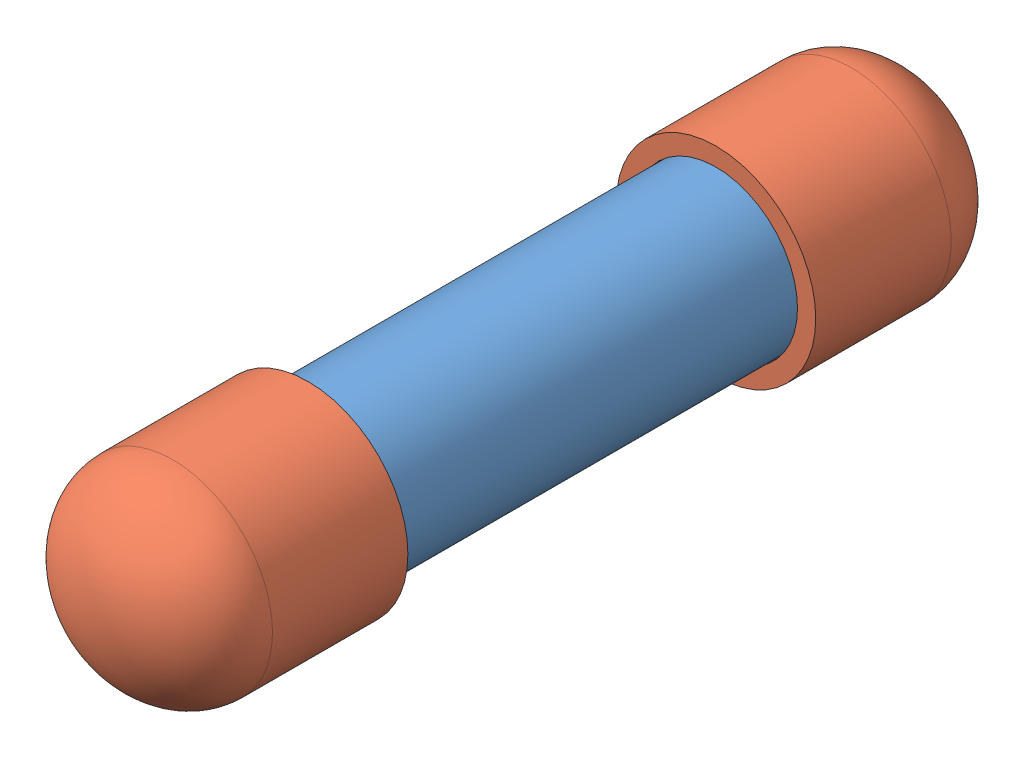
SolidWorks assembly OIL SAMPLE, configuration Default. Lengths in mm.
Overall size (41.17 41.17 172.16).
3 component instances, 2 part files, 4 mates.
Components (placement in the parent):
- 1 PVC PIPE 14CM-1: 1 PVC PIPE 14CM [48925K93] at (55.8359 74.6326 104.5055) size (33.4 33.4 140)
- 1 PVC CAP-1: 1 PVC CAP [4880K53] at (55.8359 74.6326 168.5746) x (0 0 1) z (-1 0 0) size (44.02 41.17 41.17)
- 1 PVC CAP-2: 1 PVC CAP [4880K53] at (55.8359 74.6326 40.4364) x (0 0 -1) z (1 0 0) size (44.02 41.17 41.17)
Mates (geometry in assembly coordinates):
- Coincident1: coincident anti-aligned: plane of 1 PVC PIPE 14CM-1 through (55.8359 74.6326 174.5055) normal (0 0 1); circle of 1 PVC CAP-1
- Concentric1: concentric aligned: cylinder of 1 PVC PIPE 14CM-1 through (55.8359 74.6326 174.5055) axis (0 0 -1) radius 16.7005; cylinder of 1 PVC CAP-1 through (55.8359 74.6326 146.5655) axis (0 0 -1) radius 20.5867
- Coincident2: coincident anti-aligned: plane of 1 PVC PIPE 14CM-1 through (55.8359 74.6326 34.5055) normal (0 0 -1); circle of 1 PVC CAP-2
- Concentric2: concentric anti-aligned: cylinder of 1 PVC PIPE 14CM-1 through (55.8359 74.6326 174.5055) axis (0 0 -1) radius 16.7005; cylinder of 1 PVC CAP-2 through (55.8359 74.6326 62.4455) axis (0 0 1) radius 20.5867
